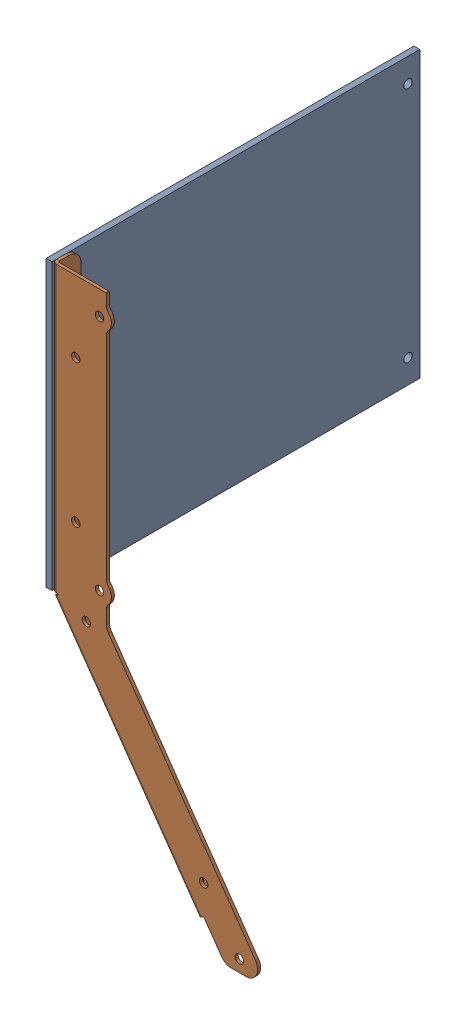
SolidWorks assembly dump, configuration Default. Lengths in mm.
Overall size (78.57 112.21 196.85).
2 component instances, 2 part files, 3 mates.
Components (placement in the parent):
- FrontPanel-1: FrontPanel [Default] at (-6.8372 76.2 -98.3851) x (0 0 -1) z (1 0 0) size (196.85 152.4 3.17) (hidden)
- DumpSideBentRight-1: DumpSideBentRight [Default] at origin size (110 279.4 13.82) (hidden)
Mates (geometry in assembly coordinates):
- Concentric1: concentric anti-aligned: circle of FrontPanel-1; circle of DumpSideBentRight-1
- Coincident4: coincident anti-aligned: plane of FrontPanel-1 through (-3.6622 76.2 -98.3851) normal (1 0 0); plane of DumpSideBentRight-1 through (-3.6622 152.146 26.5638) normal (-1 0 0)
- Concentric2: concentric aligned: cylinder of FrontPanel-1 through (-3.6622 139.7 -6.3101) axis (-1 0 0) radius 2.25; cylinder of DumpSideBentRight-1 through (-2.0747 139.7 -6.3101) axis (-1 0 0) radius 2.25
